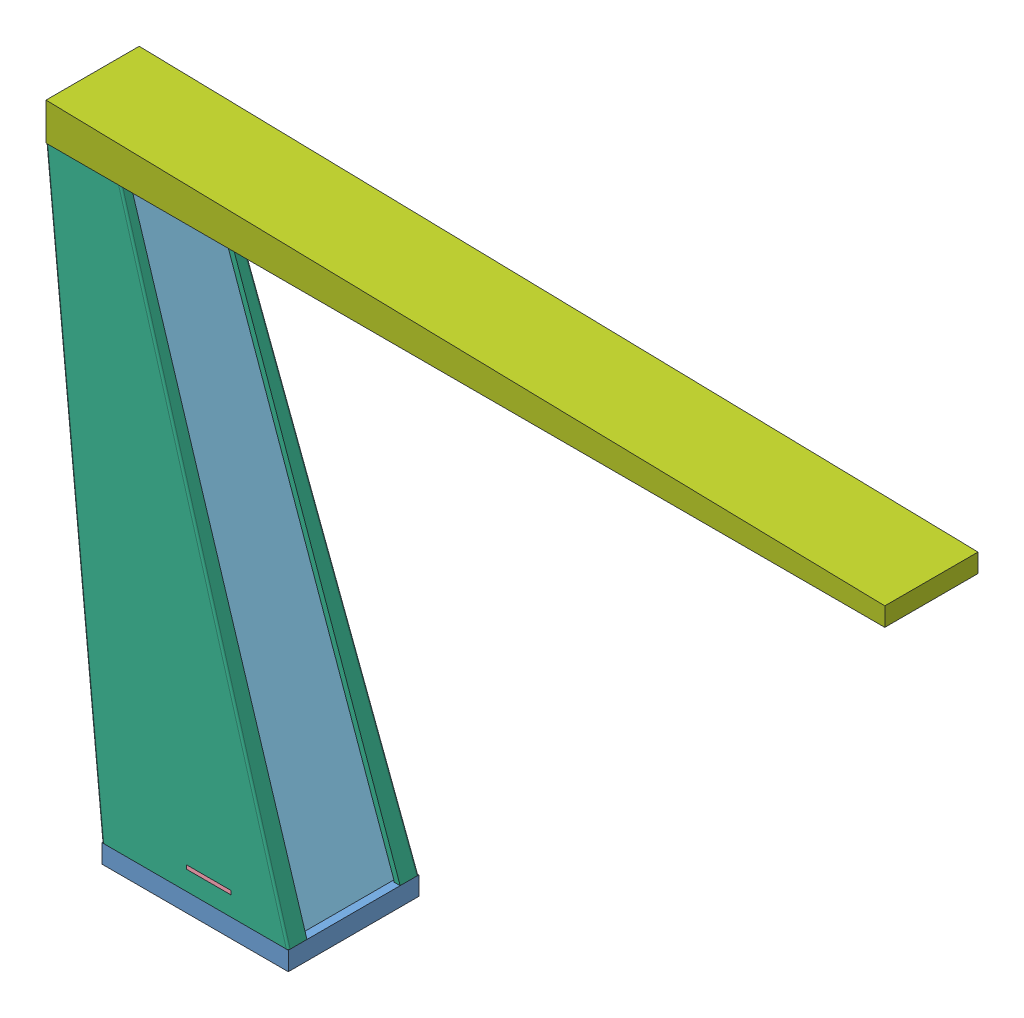
SolidWorks assembly Lamp_Assembly, configuration Exploded View. Lengths in mm.
Overall size (450 330.77 70).
13 component instances, 9 part files, 29 mates.
Components (placement in the parent):
- Acryllic Base-1: Acryllic Base [Default] at (-46.0453 -247.7362 28.6378) size (100 10 70)
- Acryllic Light Diffuser-1: Acryllic Light Diffuser [Default] at (234.0576 62.2638 -0.8622) size (400 5 11)
- 97124A242-1: 97124A242 [97124A242] at (-61.0453 -245.628 23.6378) x (-0.792859 0 0.609405) z (0 -1 0) size (6.65 6.65 20.16)
- 97124A242-2: 97124A242 [97124A242] at (-131.0453 -245.628 23.6378) x (1 0 0) z (0 -1 0) size (6.65 6.65 20.16)
- 97124A242-3: 97124A242 [97124A242] at (-61.0453 -245.628 -36.3622) x (1 0 0) z (0 -1 0) size (6.65 6.65 20.16)
- 97124A242-4: 97124A242 [97124A242] at (-131.0453 -245.628 -36.3622) x (1 0 0) z (0 -1 0) size (6.65 6.65 20.16)
- Electric Imp-1: Electric Imp [Default] at (-73.0883 -228.941 22.3413) x (1 0 0) z (0 0.033315 0.999445) size (31 3 56)
- Front Plate-1: Front Plate [Default] at (-52.3953 -237.7362 21.6378) x (0.321003 -0.947078 0) z (0 0 1) size (316 3.17 56)
- Lamp Base-1: Lamp Base [Default] at (-46.0453 -237.7362 28.6378) size (140 300 70)
- Lamp Head-1: Lamp Head [Default] at (-46.0453 -237.7362 28.6378) size (450 20 50)
- 93465A148-1: 93465A148 [93465A148] at (-171.5611 69.9942 -6.3622) x (-0.837169 0 -0.546944) z (0 1 0) size (5.74 5.74 17.06)
- 97395A451-1: 97395A451 [97395A451] at (-171.5611 61.7888 -25.1122) x (0 -1 0) z (0.065978 0 0.997821) size (19.05 3.17 3.17)
- 97395A451-2: 97395A451 [97395A451] at (-171.5611 61.7888 12.3878) x (0 1 0) z (0 0 1) size (19.05 3.17 3.17)
Mates (geometry in assembly coordinates):
- Parallel1: parallel aligned: plane of Acryllic Base-1 through (-46.0453 -247.7362 28.6378) normal (0 0 1); plane of assembly through (0 0 0) normal (0 0 1)
- Parallel2: parallel aligned: plane of Acryllic Base-1 through (-46.0453 -247.7362 28.6378) normal (0 1 0); plane of assembly through (0 0 0) normal (0 1 0)
- Parallel3: parallel aligned: plane of Acryllic Base-1 through (-46.0453 -247.7362 28.6378) normal (1 0 0); plane of assembly through (0 0 0) normal (1 0 0)
- Parallel4: parallel aligned: plane of Acryllic Light Diffuser-1 through (234.0576 62.2638 -0.8622) normal (0 0 1); plane of assembly through (0 0 0) normal (0 0 1)
- Parallel5: parallel aligned: plane of Acryllic Light Diffuser-1 through (234.0576 62.2638 -0.8622) normal (0 1 0); plane of assembly through (0 0 0) normal (0 1 0)
- Parallel6: parallel aligned: plane of Acryllic Light Diffuser-1 through (234.0576 62.2638 -0.8622) normal (1 0 0); plane of assembly through (0 0 0) normal (1 0 0)
- Concentric1: concentric anti-aligned: circle of Acryllic Base-1; circle of 97124A242-3
- Coincident22: coincident aligned: plane of Acryllic Base-1 through (-46.0453 -247.7362 28.6378) normal (0 -1 0); plane of 97124A242-3 through (-61.0453 -247.7362 -34.6096) normal (0 -1 0)
- Concentric2: concentric anti-aligned: circle of Acryllic Base-1; circle of 97124A242-4
- Coincident23: coincident aligned: plane of Acryllic Base-1 through (-46.0453 -247.7362 28.6378) normal (0 -1 0); plane of 97124A242-4 through (-131.0453 -247.7362 -34.6096) normal (0 -1 0)
- Concentric8: concentric anti-aligned: circle of Acryllic Base-1; circle of 97124A242-1
- Coincident25: coincident aligned: plane of Acryllic Base-1 through (-46.0453 -247.7362 28.6378) normal (0 -1 0); plane of 97124A242-1 through (-62.1134 -247.7362 22.2483) normal (0 -1 0)
- Concentric9: concentric anti-aligned: circle of Acryllic Base-1; circle of 97124A242-2
- Coincident26: coincident aligned: plane of Acryllic Base-1 through (-46.0453 -247.7362 28.6378) normal (0 -1 0); plane of 97124A242-2 through (-131.0453 -247.7362 25.3904) normal (0 -1 0)
- Coincident27: coincident aligned: line of Acryllic Base-1 through (-146.0453 -237.7362 28.6378) axis (1 0 0); line of Lamp Base-1 through (-145.032 -237.7362 28.6378) axis (1 0 0)
- Coincident28: coincident aligned: line of Acryllic Base-1 through (-146.0453 -237.7362 -41.3622) axis (0 0 1); line of Lamp Base-1 through (-146.0453 -237.7362 -40.3572) axis (0 0 1)
- Coincident34: coincident anti-aligned: line of Electric Imp-1 through (-101.0883 -225.7428 28.2381) axis (1 0 0); line of Lamp Base-1 through (-77.0883 -225.7428 28.2381) axis (-1 0 0)
- Coincident35: coincident aligned: line of Electric Imp-1 through (-101.0883 -225.7428 28.2381) axis (0 -0.999445 0.033315); line of Lamp Base-1 through (-101.0883 -225.7428 28.2381) axis (0 -0.999445 0.033315)
- Coincident36: coincident anti-aligned: line of Acryllic Light Diffuser-1 through (234.0576 62.2638 -0.8622) axis (0 0 -1); line of Lamp Head-1 through (234.0576 62.2638 -11.8622) axis (0 0 1)
- Coincident37: coincident aligned: line of Acryllic Light Diffuser-1 through (234.0576 67.2638 -0.8622) axis (0 -1 0); line of Lamp Head-1 through (234.0576 70.2638 -0.8622) axis (0 -1 0)
- Coincident42: coincident: point of Front Plate-1; point of Lamp Base-1
- Concentric11: concentric aligned: circle of Lamp Base-1; circle of 93465A148-1
- Coincident44: coincident anti-aligned: plane of Lamp Base-1 through (-177.7394 57.2942 1.1378) normal (0 -1 0); plane of 93465A148-1 through (-171.5611 57.2942 -6.3622) normal (0 1 0)
- Concentric14: concentric aligned: circle of Lamp Base-1; circle of 97395A451-1
- Coincident45: coincident anti-aligned: circle of Lamp Base-1; plane of 97395A451-1 through (-171.5611 52.2638 -25.1122) normal (0 -1 0)
- Coincident46: coincident anti-aligned: circle of Lamp Base-1; plane of 97395A451-2 through (-171.5611 52.2638 12.3878) normal (0 -1 0)
- Concentric15: concentric aligned: circle of Lamp Base-1; circle of 97395A451-2
- Coincident47: coincident aligned: line of Lamp Base-1 through (-186.0453 62.2638 -30.3572) axis (0 0 1); line of Lamp Head-1 through (-186.0453 62.2638 -31.3622) axis (0 0 1)
- Coincident48: coincident aligned: line of Lamp Base-1 through (-185.032 62.2638 18.6378) axis (1 0 0); line of Lamp Head-1 through (-186.0453 62.2638 18.6378) axis (1 0 0)
